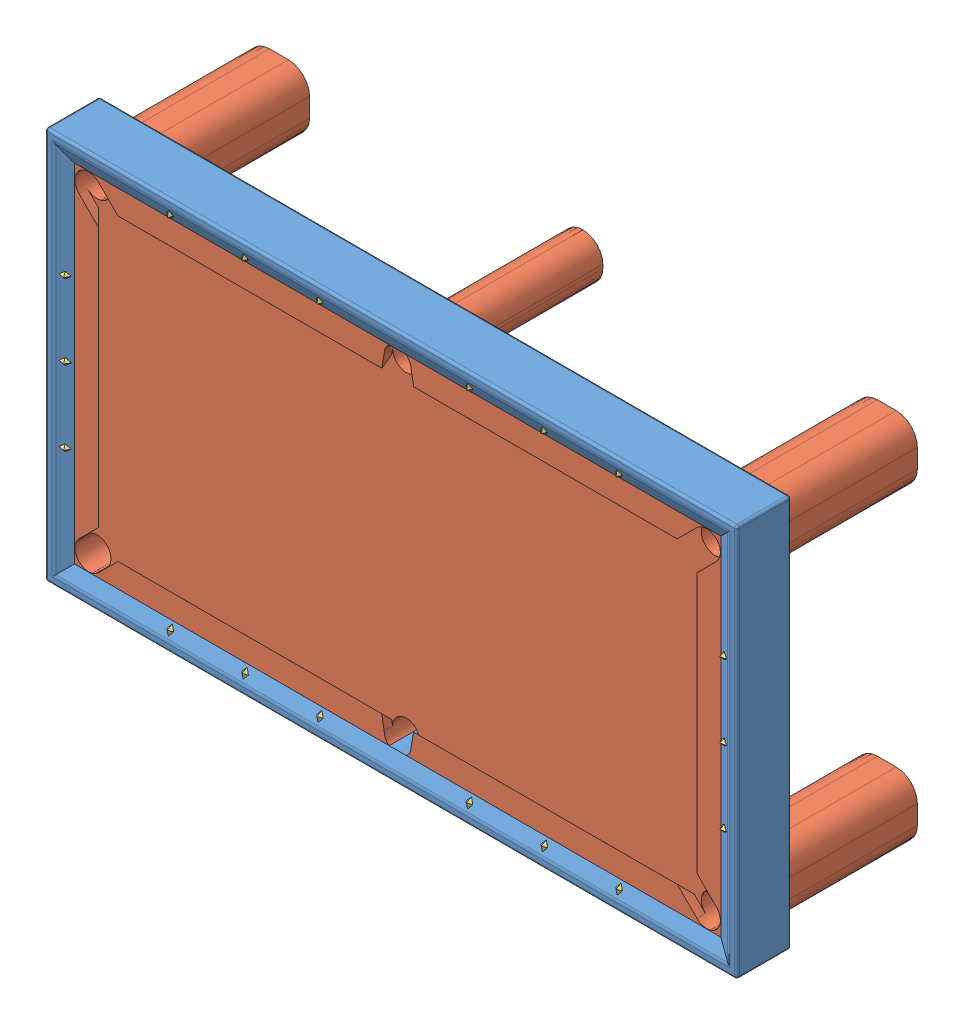
SolidWorks assembly Złożenie2, configuration Domyślna. Lengths in mm.
Overall size (3099.9 2615.43 3210.06).
21 component instances, 3 part files, 27 mates.
Components (placement in the parent):
- Część1-1: Część1 [Domyślna] at (-85.9273 -105.2512 -308) size (2936 1666 230)
- PoolTableModel-1: PoolTableModel [Domyślna] at (-152.226 -105.8921 51.0215) size (2840 1570 786)
- Złożenie3^Złożenie2-1: Złożenie3^Złożenie2 [Domyślna] at (-1097.6573 655.5973 106.062) x (-0.708886 -0.298083 0.63924) z (-0.705323 0.299588 -0.642469) size (2214.79 1428.26 2205.7)
  - Diamond-1: Diamond [Domyślna] at origin size (20 39.8 19.8)
  - Diamond-2: Diamond [Domyślna] at (-225.0712 0 -223.9402) size (20 39.8 19.8)
  - Diamond-3: Diamond [Domyślna] at (-450.1424 0 -447.8804) size (20 39.8 19.8)
  - Diamond-4: Diamond [Domyślna] at (-900.2848 0 -895.7607) size (20 39.8 19.8)
  - Diamond-5: Diamond [Domyślna] at (-1125.356 0 -1119.7009) size (20 39.8 19.8)
  - Diamond-6: Diamond [Domyślna] at (-1350.4272 0 -1343.6411) size (20 39.8 19.8)
  - Diamond-7: Diamond [Domyślna] at (453.667 -1379.3558 -455.9582) x (0.822294 0.540309 0.178604) z (0.178604 -0.543038 0.820494) size (20 39.8 19.8)
  - Diamond-8: Diamond [Domyślna] at (228.5958 -1379.3558 -679.8984) x (0.822294 0.540309 0.178604) z (0.178604 -0.543038 0.820494) size (20 39.8 19.8)
  - Diamond-9: Diamond [Domyślna] at (3.5246 -1379.3558 -903.8386) x (0.822294 0.540309 0.178604) z (0.178604 -0.543038 0.820494) size (20 39.8 19.8)
  - Diamond-10: Diamond [Domyślna] at (-446.6178 -1379.3558 -1351.719) x (0.822294 0.540309 0.178604) z (0.178604 -0.543038 0.820494) size (20 39.8 19.8)
  - Diamond-11: Diamond [Domyślna] at (-671.689 -1379.3558 -1575.6591) x (0.822294 0.540309 0.178604) z (0.178604 -0.543038 0.820494) size (20 39.8 19.8)
  - Diamond-12: Diamond [Domyślna] at (-896.7602 -1379.3558 -1799.5993) x (0.822294 0.540309 0.178604) z (0.178604 -0.543038 0.820494) size (20 39.8 19.8)
  - Diamond-13: Diamond [Domyślna] at (642.9147 -983.7909 -7.4574) x (-0.013985 0.912623 -0.408563) z (-0.408563 0.367721 0.835379) size (20 39.8 19.8)
  - Diamond-14: Diamond [Domyślna] at (548.2735 -696.0382 87.6618) x (-0.013985 0.912623 -0.408563) z (-0.408563 0.367721 0.835379) size (20 39.8 19.8)
  - Diamond-15: Diamond [Domyślna] at (453.6323 -408.2855 182.781) x (-0.013985 0.912623 -0.408563) z (-0.408563 0.367721 0.835379) size (20 39.8 19.8)
  - Diamond-16: Diamond [Domyślna] at (-1336.2591 -983.7909 -1976.6856) x (0.408628 0.912623 0.011927) z (-0.83331 0.367721 0.412766) size (20 39.8 19.8)
  - Diamond-17: Diamond [Domyślna] at (-1430.9003 -696.0382 -1881.5664) x (0.408628 0.912623 0.011927) z (-0.83331 0.367721 0.412766) size (20 39.8 19.8)
  - Diamond-18: Diamond [Domyślna] at (-1525.5415 -408.2855 -1786.4472) x (0.408628 0.912623 0.011927) z (-0.83331 0.367721 0.412766) size (20 39.8 19.8)
Mates (geometry in assembly coordinates):
- Równolegle1: parallel anti-aligned: plane of Część1-1 through (-1524.1751 -842.3781 115) normal (0 1 0); plane of PoolTableModel-1 through (-1572.226 -890.8921 87.0215) normal (0 -1 0)
- Równolegle2: parallel anti-aligned: plane of Część1-1 through (-1524.1751 -842.3781 115) normal (1 0 0); plane of PoolTableModel-1 through (-1572.226 -890.8921 87.0215) normal (-1 0 0)
- Wspólnie4: coincident: line of Część1-1 through (-1524.1751 -842.3781 87.0215) axis (1 0 0); plane of PoolTableModel-1 through (-152.226 -105.8921 87.0215) normal (0 0 1)
- Wspólnie31: coincident: point of Część1-1; point of Złożenie3^Złożenie2-1/Diamond-1
- Wspólnie32: coincident anti-aligned: line of Część1-1 through (-1104.6751 631.6219 87.0215) axis (0 0.906308 0.422618); line of Złożenie3^Złożenie2-1/Diamond-1 through (-1104.6751 676.6436 108.0155) axis (0 -0.906308 -0.422618)
- Wspólnie33: coincident anti-aligned: plane of Część1-1 through (-1524.1751 631.6219 87.0215) normal (0 -0.422618 0.906308); plane of Złożenie3^Złożenie2-1/Diamond-1 through (-1097.6573 658.6081 99.6054) normal (0 0.422618 -0.906308)
- Wspólnie34: coincident: point of Część1-1; point of Złożenie3^Złożenie2-1/Diamond-2
- Wspólnie35: coincident: point of Część1-1; point of Złożenie3^Złożenie2-1/Diamond-3
- Wspólnie36: coincident: point of Część1-1; point of Złożenie3^Złożenie2-1/Diamond-4
- Wspólnie37: coincident: point of Część1-1; point of Złożenie3^Złożenie2-1/Diamond-5
- Wspólnie38: coincident: point of Część1-1; point of Złożenie3^Złożenie2-1/Diamond-6
- Wspólnie39: coincident: point of Część1-1; point of Złożenie3^Złożenie2-1/Diamond-7
- Wspólnie40: coincident aligned: line of Część1-1 through (-1104.6751 -842.3781 87.0215) axis (0 -0.906308 0.422618); line of Złożenie3^Złożenie2-1/Diamond-7 through (-1104.6751 -851.3287 91.1953) axis (0 -0.906308 0.422618)
- Wspólnie41: coincident: point of Część1-1; point of Złożenie3^Złożenie2-1/Diamond-8
- Wspólnie42: coincident: point of Część1-1; point of Złożenie3^Złożenie2-1/Diamond-9
- Wspólnie43: coincident: point of Część1-1; point of Złożenie3^Złożenie2-1/Diamond-10
- Wspólnie44: coincident: point of Część1-1; point of Złożenie3^Złożenie2-1/Diamond-11
- Wspólnie45: coincident: point of Część1-1; point of Złożenie3^Złożenie2-1/Diamond-12
- Wspólnie46: coincident: point of Część1-1; point of Złożenie3^Złożenie2-1/Diamond-13
- Wspólnie47: coincident aligned: line of Część1-1 through (-1524.1751 -422.8781 87.0215) axis (-0.906308 0 0.422618); line of Złożenie3^Złożenie2-1/Diamond-13 through (-1533.1257 -422.8781 91.1953) axis (-0.906308 0 0.422618)
- Wspólnie48: coincident anti-aligned: plane of Część1-1 through (-1524.1751 -842.3781 87.0215) normal (0.422618 0 0.906308); plane of Złożenie3^Złożenie2-1/Diamond-13 through (-1551.1612 -429.8958 99.6054) normal (-0.422618 0 -0.906308)
- Wspólnie49: coincident: point of Część1-1; point of Złożenie3^Złożenie2-1/Diamond-14
- Wspólnie50: coincident: point of Część1-1; point of Złożenie3^Złożenie2-1/Diamond-15
- Wspólnie51: coincident: point of Złożenie3^Złożenie2-1/Diamond-16; point of assembly
- Wspólnie52: coincident anti-aligned: line of Złożenie3^Złożenie2-1/Diamond-16 through (1264.8466 -422.8781 108.0155) axis (-0.906308 0 -0.422618); line of assembly
- Wspólnie53: coincident: point of Złożenie3^Złożenie2-1/Diamond-17; point of assembly
- Wspólnie54: coincident: point of Złożenie3^Złożenie2-1/Diamond-18; point of assembly
